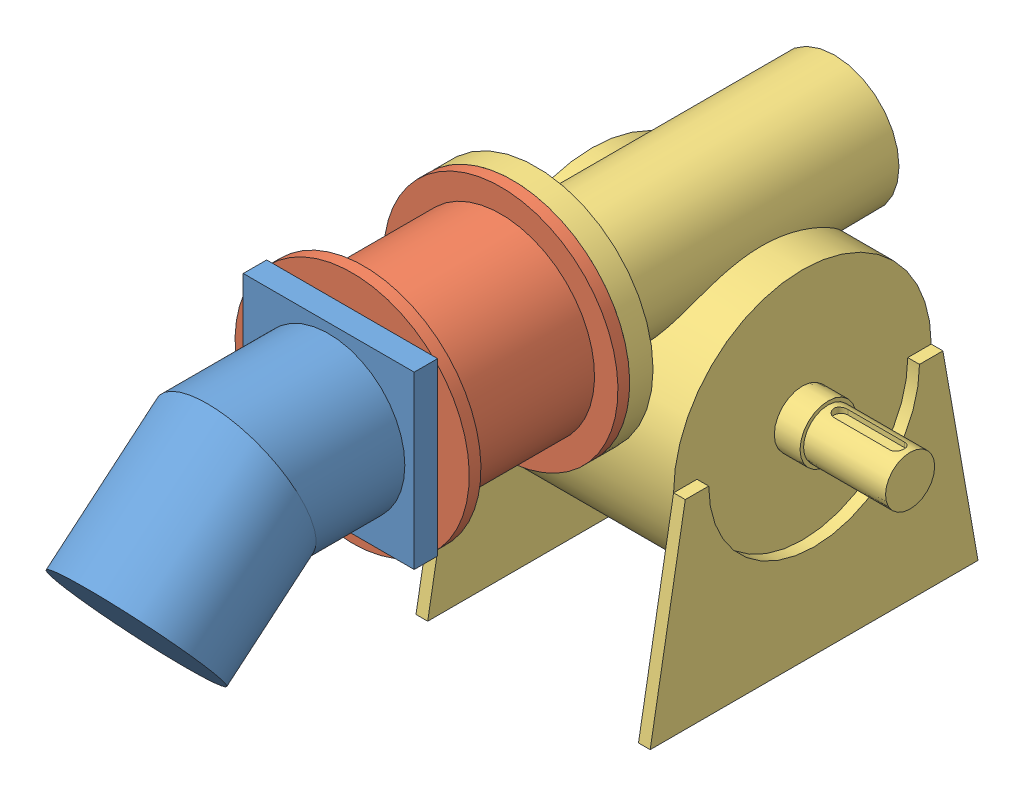
SolidWorks assembly hydraulic_motor_AA2FM_32, configuration Default. Lengths in mm.
Overall size (264.5 380 660.52).
3 component instances, 3 part files, 7 mates.
Components (placement in the parent):
- Motor-1: Motor [Default] at origin size (146 193.5 238.75)
- Flange_Adapter-1: Flange_Adapter [Default] x (0 0 -1) z (0 1 0) size (137 200 200)
- Wormgear-1: Wormgear [Default] at (0 0 -157) size (264.5 380 297.48)
Mates (geometry in assembly coordinates):
- Coincident1: coordinate: point of Motor-1
- Concentric1: concentric anti-aligned: cylinder of Motor-1 through (0 0 -12.7) axis (0 0 1) radius 63.5; cylinder of Flange_Adapter-1 through (0 0 -71.925) axis (0 0 -1) radius 60
- Coincident2: coincident anti-aligned: plane of Motor-1 through (0 0 0) normal (0 0 -1); plane of Flange_Adapter-1 through (-100 0 0) normal (0 0 1)
- Coincident3: coincident anti-aligned: plane of Flange_Adapter-1 through (-100 0 -137) normal (0 0 -1); plane of Wormgear-1 through (0 0 -137) normal (0 0 1)
- Concentric2: concentric aligned: cylinder of Flange_Adapter-1 through (0 0 -71.925) axis (0 0 -1) radius 80; cylinder of Wormgear-1 through (0 0 -137) axis (0 0 -1) radius 100
- Coincident4: coincident aligned: plane of Motor-1 through (0 0 0) normal (1 0 0); plane of Wormgear-1 through (0 0 -157) normal (1 0 0)
- Coincident5: coincident anti-aligned: plane of Motor-1 through (0 0 0) normal (1 0 0); plane of Flange_Adapter-1 through (0 0 0) normal (-1 0 0)
